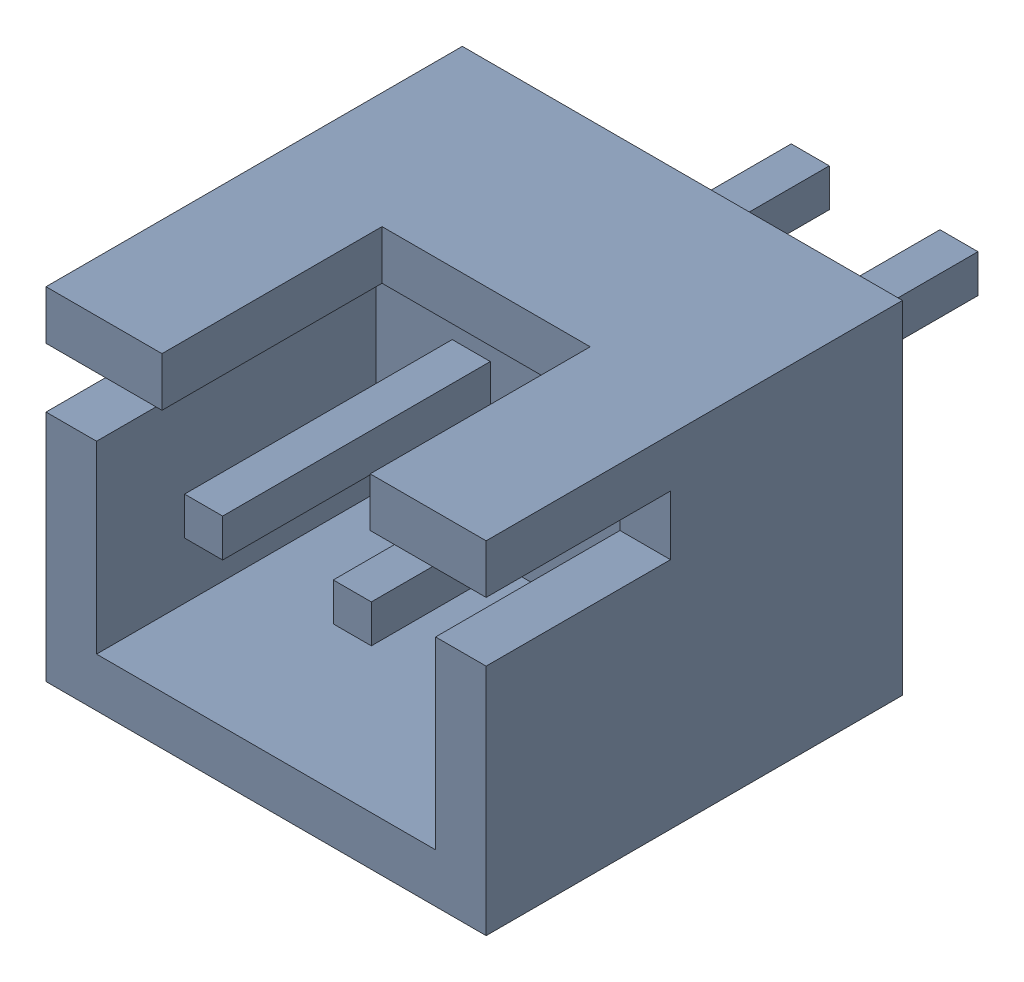
SolidWorks assembly SWITCH, configuration Défaut. Lengths in mm.
Overall size (7.4 5.75 10.4).
2 component instances, 1 part files, 0 mates.
Components (placement in the parent):
- Open CASCADE STEP translator 6.8 1.30.1-1: Open CASCADE STEP translator 6.8 1.30.1 [Défaut] at origin size (7.4 5.75 10.4)
  - Body_1_14-1: Body_1_14 [Défaut] at (-1.25 -0.5 0) x (-1 0 0) z (0 1 0) size (7.4 10.4 5.75)
